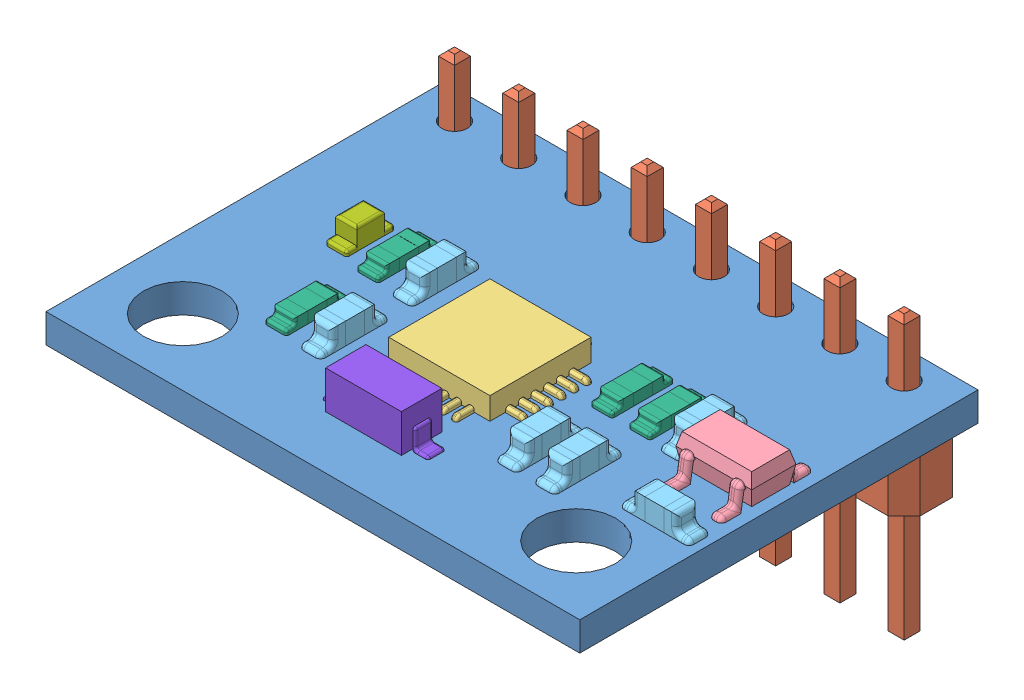
SolidWorks assembly MPU 6050 IMU, configuration Default. Lengths in mm.
Overall size (21.11 11.18 15.88).
23 component instances, 8 part files, 33 mates.
Components (placement in the parent):
- Base-1: Base [Default] at (7.2489 10.9584 16.5726) size (21.11 1.14 15.75)
- pin header-1: pin header [Default] at (16.0246 10.3869 9.8416) x (-1 0 0) z (0 0 1) size (2.54 11.18 2.54)
- pin header-2: pin header [Default] at (13.4846 10.3869 9.8416) x (-1 0 0) z (0 0 1) size (2.54 11.18 2.54)
- pin header-3: pin header [Default] at (10.9446 10.3869 9.8416) x (-1 0 0) z (0 0 1) size (2.54 11.18 2.54)
- pin header-4: pin header [Default] at (8.4046 10.3869 9.8416) x (-1 0 0) z (0 0 1) size (2.54 11.18 2.54)
- pin header-5: pin header [Default] at (5.8646 10.3869 9.8416) x (-1 0 0) z (0 0 1) size (2.54 11.18 2.54)
- pin header-6: pin header [Default] at (3.3246 10.3869 9.8416) x (-1 0 0) z (0 0 1) size (2.54 11.18 2.54)
- pin header-7: pin header [Default] at (0.7846 10.3869 9.8416) x (-1 0 0) z (0 0 1) size (2.54 11.18 2.54)
- pin header-8: pin header [Default] at (-1.7554 10.3869 9.8416) x (-1 0 0) z (0 0 1) size (2.54 11.18 2.54)
- sensor chip-1: sensor chip [Default] at (7.2489 11.5499 17.4466) size (5.4 0.9 5.4)
- S2NH chip-1: S2NH chip [Default] at (16.1026 12.3799 16.5726) size (3 1.35 3.65)
- Resistor small-3: Resistor small [Default] at (16.1026 11.5314 19.3726) size (2.75 0.99 1)
- Resistor small-4: Resistor small [Default] at (13.9776 11.5314 15.6976) x (0 0 -1) z (1 0 0) size (2.75 0.99 1)
- Resistor small black-3: Resistor small black [Default] at (12.6276 11.5299 15.6976) x (0 0 1) z (-1 0 0) size (2.45 0.6 1.02)
- Resistor small black-4: Resistor small black [Default] at (11.1276 11.5299 15.6976) x (0 0 1) z (-1 0 0) size (2.45 0.6 1.02)
- Resistor small-5: Resistor small [Default] at (12.6276 11.5314 19.3216) x (0 0 -1) z (1 0 0) size (2.75 0.99 1)
- Resistor small-6: Resistor small [Default] at (11.1276 11.5314 19.3216) x (0 0 -1) z (1 0 0) size (2.75 0.99 1)
- Resistor small-7: Resistor small [Default] at (3.3702 11.5314 19.3216) x (0 0 -1) z (1 0 0) size (2.75 0.99 1)
- Resistor small black-5: Resistor small black [Default] at (1.8702 11.5299 15.6968) x (0 0 -1) z (1 0 0) size (2.45 0.6 1.02)
- Resistor small-8: Resistor small [Default] at (3.3702 11.5314 15.6976) x (0 0 1) z (-1 0 0) size (2.75 0.99 1)
- Small LED-1: Small LED [Default] at (0.3652 11.5299 15.6976) size (0.85 0.84 1.9)
- Resistor small black-6: Resistor small black [Default] at (1.8702 11.5299 19.3216) x (0 0 1) z (-1 0 0) size (2.45 0.6 1.02)
- Resistor black-1: Resistor black [Default] at (7.2489 12.3799 21.6466) size (4.2 1.6 1.6)
Mates (geometry in assembly coordinates):
- Concentric1: concentric: cylinder of Base-1 through (16.0246 11.5299 9.8416) axis (0 -1 0) radius 0.508; point of pin header-1
- Coincident4: coincident anti-aligned: plane of Base-1 through (7.2489 10.3869 16.5726) normal (0 -1 0); plane of pin header-1 through (16.0246 10.3869 9.8416) normal (0 1 0)
- Parallel1: parallel aligned: plane of Base-1 through (17.8026 11.5299 24.4466) normal (1 0 0); plane of pin header-1 through (17.2946 7.8469 10.4766) normal (1 0 0)
- Coincident6: coincident anti-aligned: plane of Base-1 through (7.2489 11.5299 16.5726) normal (0 1 0); plane of sensor chip-1 through (7.2489 11.5299 17.4466) normal (0 -1 0)
- Coincident7: coincident aligned: plane of Base-1 through (7.2489 10.9584 16.5726) normal (1 0 0); plane of sensor chip-1 through (7.2489 11.5499 17.4466) normal (1 0 0)
- Distance1: distance = 5 mm aligned: plane of sensor chip-1 through (5.2489 12.4299 19.4466) normal (0 0 1); plane of Base-1 through (-3.3048 11.5299 24.4466) normal (0 0 1)
- Coincident8: coincident anti-aligned: plane of Base-1 through (7.2489 11.5299 16.5726) normal (0 1 0); plane of S2NH chip-1 through (16.1026 11.5299 16.5726) normal (0 -1 0)
- Coincident9: coincident aligned: plane of Base-1 through (7.2489 10.9584 16.5726) normal (0 0 1); plane of S2NH chip-1 through (16.1026 12.3799 16.5726) normal (0 0 1)
- Distance2: distance = 0.2 mm: line of S2NH chip-1 through (17.6026 12.3799 17.4476) axis (0 0 -1); plane of Base-1 through (17.8026 11.5299 24.4466) normal (1 0 0)
- Coincident19: coincident anti-aligned: plane of Base-1 through (7.2489 11.5299 16.5726) normal (0 1 0); plane of Resistor small-3 through (16.9776 11.5299 19.8026) normal (0 -1 0)
- Coincident20: coincident aligned: plane of S2NH chip-1 through (16.1026 12.3799 16.5726) normal (1 0 0); plane of Resistor small-3 through (16.1026 11.5314 19.3726) normal (1 0 0)
- Distance5: distance = 1.5 mm: line of S2NH chip-1 through (15.3258 12.3799 17.4476) axis (1 0 0); plane of Resistor small-3 through (16.4776 11.5314 18.9476) normal (0 0 -1)
- Coincident22: coincident anti-aligned: plane of Base-1 through (7.2489 11.5299 16.5726) normal (0 1 0); plane of Resistor small-4 through (14.4076 11.5299 14.8226) normal (0 -1 0)
- Coincident24: coincident: line of S2NH chip-1 through (16.8794 12.3799 15.6976) axis (-1 0 0); plane of Resistor small-4 through (13.9776 11.5314 15.6976) normal (0 0 -1)
- Distance6: distance = 0.2 mm: plane of Resistor small-4 through (14.4026 11.5314 15.3226) normal (1 0 0); line of S2NH chip-1 through (14.6026 12.3799 15.6976) axis (0 0 1)
- Coincident26: coincident anti-aligned: plane of Base-1 through (7.2489 11.5299 16.5726) normal (0 1 0); plane of Resistor small black-3 through (12.2026 11.5299 16.0726) normal (0 -1 0)
- Coincident28: coincident anti-aligned: plane of Resistor small-4 through (13.9776 11.5314 15.6976) normal (0 0 -1); plane of Resistor small black-3 through (12.6276 11.5299 15.6976) normal (0 0 1)
- Distance7: distance = 0.5 mm anti-aligned: plane of Resistor small-4 through (13.5526 11.5314 15.3226) normal (-1 0 0); plane of Resistor small black-3 through (13.0526 11.5299 16.0726) normal (1 0 0)
- Coincident30: coincident anti-aligned: plane of Base-1 through (7.2489 11.5299 16.5726) normal (0 1 0); plane of Resistor small-5 through (13.0576 11.5299 18.4466) normal (0 -1 0)
- Coincident31: coincident anti-aligned: plane of Resistor small black-3 through (12.6276 11.5299 15.6976) normal (-1 0 0); plane of Resistor small-5 through (12.6276 11.5314 19.3216) normal (1 0 0)
- Distance8: distance = 4.25 mm aligned: plane of Resistor small-5 through (12.6276 11.5314 20.1966) normal (0 0 1); plane of Base-1 through (-3.3048 11.5299 24.4466) normal (0 0 1)
- Coincident33: coincident anti-aligned: plane of Base-1 through (7.2489 11.5299 16.5726) normal (0 1 0); plane of Resistor small-8 through (2.9402 11.5299 14.8226) normal (0 -1 0)
- Coincident34: coincident anti-aligned: plane of Resistor small-7 through (3.3702 11.5314 19.3216) normal (1 0 0); plane of Resistor small-8 through (3.3702 11.5314 15.6976) normal (-1 0 0)
- Coincident36: coincident: line of S2NH chip-1 through (15.8794 12.3799 15.6976) axis (-1 0 0); plane of Resistor small-8 through (3.3702 11.5314 15.6976) normal (0 0 1)
- Coincident37: coincident anti-aligned: plane of Base-1 through (7.2489 11.5299 16.5726) normal (0 1 0); plane of Small LED-1 through (0.3652 11.5299 15.6976) normal (0 -1 0)
- Coincident38: coincident: line of S2NH chip-1 through (15.8794 12.3799 15.6976) axis (-1 0 0); plane of Small LED-1 through (0.3652 11.5299 15.6976) normal (0 0 1)
- Distance9: distance = 1.5 mm aligned: plane of Small LED-1 through (-0.0548 12.3699 16.2476) normal (-1 0 0); plane of Resistor small black-5 through (1.4452 11.5299 15.3218) normal (-1 0 0)
- Coincident40: coincident anti-aligned: plane of Base-1 through (7.2489 11.5299 16.5726) normal (0 1 0); plane of Resistor small black-6 through (1.4452 11.5299 20.4824) normal (0 -1 0)
- Coincident41: coincident anti-aligned: plane of Resistor small black-5 through (1.8702 11.5299 15.6968) normal (1 0 0); plane of Resistor small black-6 through (1.8702 11.5299 20.1074) normal (-1 0 0)
- Coincident42: coincident anti-aligned: plane of Resistor small-7 through (3.3702 11.5314 19.3216) normal (0 0 -1); plane of Resistor small black-6 through (1.8702 11.5299 19.3216) normal (0 0 1)
- Coincident43: coincident: plane of Base-1 through (7.2489 11.5299 16.5726) normal (0 1 0); plane of Resistor black-1 through (5.6489 11.5299 21.9966) normal (0 -1 0)
- Coincident44: coincident: plane of Base-1 through (7.2489 10.9584 16.5726) normal (1 0 0); plane of Resistor black-1 through (7.2489 12.3799 21.6466) normal (1 0 0)
- Distance10: distance = 2 mm aligned: plane of Resistor black-1 through (5.7489 13.1299 22.4466) normal (0 0 1); plane of Base-1 through (-3.3048 11.5299 24.4466) normal (0 0 1)
